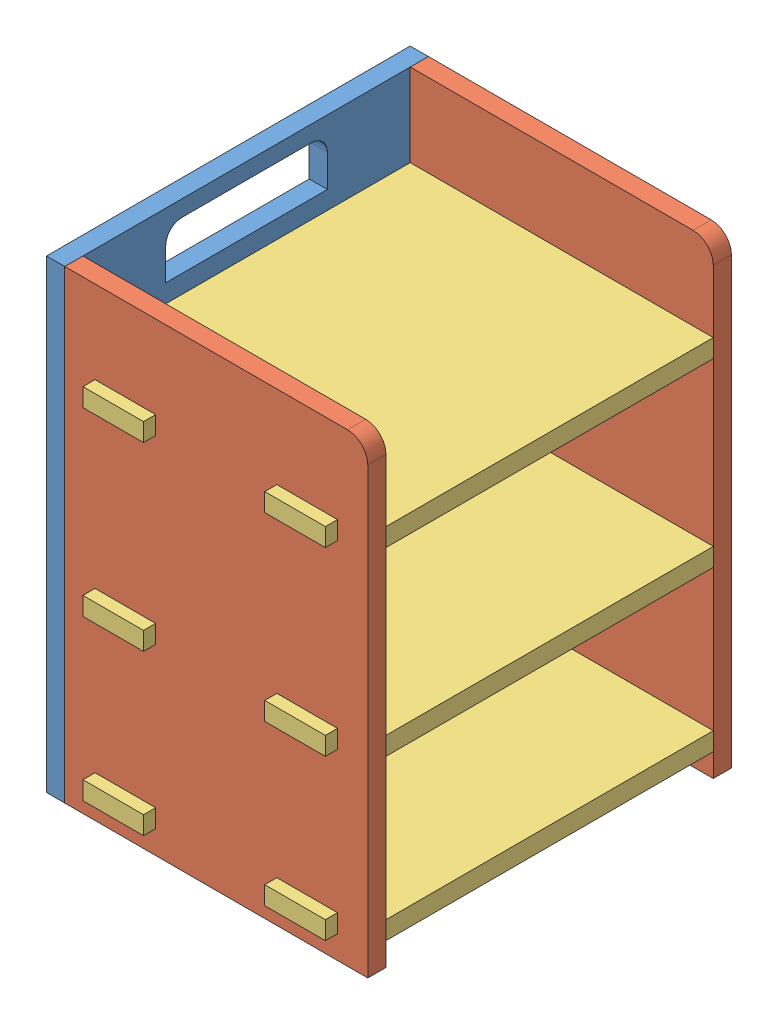
SolidWorks assembly frame_assembly_complete, configuration Default. Lengths in mm.
Overall size (82.5 115 96).
9 component instances, 4 part files, 18 mates.
Components (placement in the parent):
- frame_assembly-1: frame_assembly [Default] at (-13.1345 10.3253 139.5488) size (79.5 115 90)
  - base_frame-1: base_frame [Default] at origin size (4.5 115 90)
  - side_layer-1: side_layer [Default] at (42 57.5 -4.5) size (75 115 4.5)
- frame_layer_v2-1: frame_layer_v2 [Default] at (28.8655 100.3253 94.5488) x (0 0 -1) z (1 0 0) size (96 4.5 82.5)
- side_layer-4: side_layer [Default] at (28.8655 67.8253 49.5488) size (75 115 4.5)
- frame_layer_v2-2: frame_layer_v2 [Default] at (28.8655 55.5753 94.5488) x (0 0 -1) z (1 0 0) size (96 4.5 82.5)
- frame_layer_v2-3: frame_layer_v2 [Default] at (28.8655 16.0753 94.5488) x (0 0 -1) z (1 0 0) size (96 4.5 82.5)
- motor_surface-2: motor_surface [Default] at (29.7823 10.3253 76.9612) x (0 0 -1) z (1 0 0) size (25 5.75 35)
- motor_surface-3: motor_surface [Default] at (28.5475 10.3253 132.9612) x (0 0 -1) z (1 0 0) size (25 5.75 35)
Mates (geometry in assembly coordinates):
- Coincident38: coincident anti-aligned: plane of frame_assembly-1/side_layer-1 through (28.8655 67.8253 135.0488) normal (0 0 -1); plane of frame_layer_v2-1 through (28.8655 104.8253 135.0488) normal (0 0 1)
- Coincident39: coincident anti-aligned: plane of frame_assembly-1/base_frame-1 through (-8.6345 10.3253 139.5488) normal (1 0 0); plane of frame_layer_v2-1 through (-8.6345 104.8253 94.5488) normal (-1 0 0)
- Coincident40: coincident anti-aligned: plane of frame_assembly-1/base_frame-1 through (-8.6345 10.3253 139.5488) normal (1 0 0); plane of side_layer-4 through (-8.6345 67.8253 54.0488) normal (-1 0 0)
- Coincident41: coincident anti-aligned: line of frame_assembly-1/base_frame-1 through (-8.6345 10.3253 49.5488) axis (0 1 0); line of side_layer-4 through (-8.6345 125.3253 49.5488) axis (0 -1 0)
- Coincident42: coincident aligned: line of frame_assembly-1/base_frame-1 through (-8.6345 125.3253 139.5488) axis (0 0 -1); line of side_layer-4 through (-8.6345 125.3253 54.0488) axis (0 0 -1)
- Coincident45: coincident anti-aligned: plane of frame_layer_v2-1 through (28.8655 100.3253 94.5488) normal (0 -1 0); plane of side_layer-4 through (28.8655 100.3253 54.0488) normal (0 1 0)
- Coincident46: coincident anti-aligned: plane of side_layer-4 through (28.8655 67.8253 54.0488) normal (0 0 1); plane of frame_layer_v2-2 through (28.8655 60.0753 54.0488) normal (0 0 -1)
- Coincident47: coincident anti-aligned: plane of frame_assembly-1/side_layer-1 through (28.8655 67.8253 135.0488) normal (0 0 -1); plane of frame_layer_v2-2 through (28.8655 60.0753 135.0488) normal (0 0 1)
- Coincident48: coincident anti-aligned: plane of frame_assembly-1/base_frame-1 through (-8.6345 10.3253 139.5488) normal (1 0 0); plane of frame_layer_v2-2 through (-8.6345 60.0753 94.5488) normal (-1 0 0)
- Coincident49: coincident anti-aligned: plane of side_layer-4 through (28.8655 60.0753 54.0488) normal (0 -1 0); plane of frame_layer_v2-2 through (28.8655 60.0753 94.5488) normal (0 1 0)
- Coincident50: coincident anti-aligned: plane of side_layer-4 through (28.8655 67.8253 54.0488) normal (0 0 1); plane of frame_layer_v2-3 through (28.8655 20.5753 54.0488) normal (0 0 -1)
- Coincident51: coincident anti-aligned: plane of frame_assembly-1/side_layer-1 through (28.8655 67.8253 135.0488) normal (0 0 -1); plane of frame_layer_v2-3 through (28.8655 20.5753 135.0488) normal (0 0 1)
- Coincident52: coincident anti-aligned: plane of frame_assembly-1/base_frame-1 through (-8.6345 10.3253 139.5488) normal (1 0 0); plane of frame_layer_v2-3 through (-8.6345 20.5753 94.5488) normal (-1 0 0)
- Coincident53: coincident anti-aligned: plane of side_layer-4 through (28.8655 16.0753 54.0488) normal (0 1 0); plane of frame_layer_v2-3 through (28.8655 16.0753 94.5488) normal (0 -1 0)
- Coincident56: coincident anti-aligned: plane of frame_layer_v2-3 through (28.8655 16.0753 94.5488) normal (0 -1 0); plane of motor_surface-2 through (29.7823 16.0753 76.9612) normal (0 1 0)
- Coincident57: coincident anti-aligned: plane of side_layer-4 through (28.8655 67.8253 54.0488) normal (0 0 1); plane of motor_surface-2 through (10.9292 16.0753 54.0488) normal (0 0 -1)
- Coincident58: coincident anti-aligned: plane of frame_assembly-1/side_layer-1 through (28.8655 67.8253 135.0488) normal (0 0 -1); plane of motor_surface-3 through (9.6944 16.0753 135.0488) normal (0 0 1)
- Coincident59: coincident anti-aligned: plane of frame_layer_v2-3 through (28.8655 16.0753 94.5488) normal (0 -1 0); plane of motor_surface-3 through (28.5475 16.0753 132.9612) normal (0 1 0)
